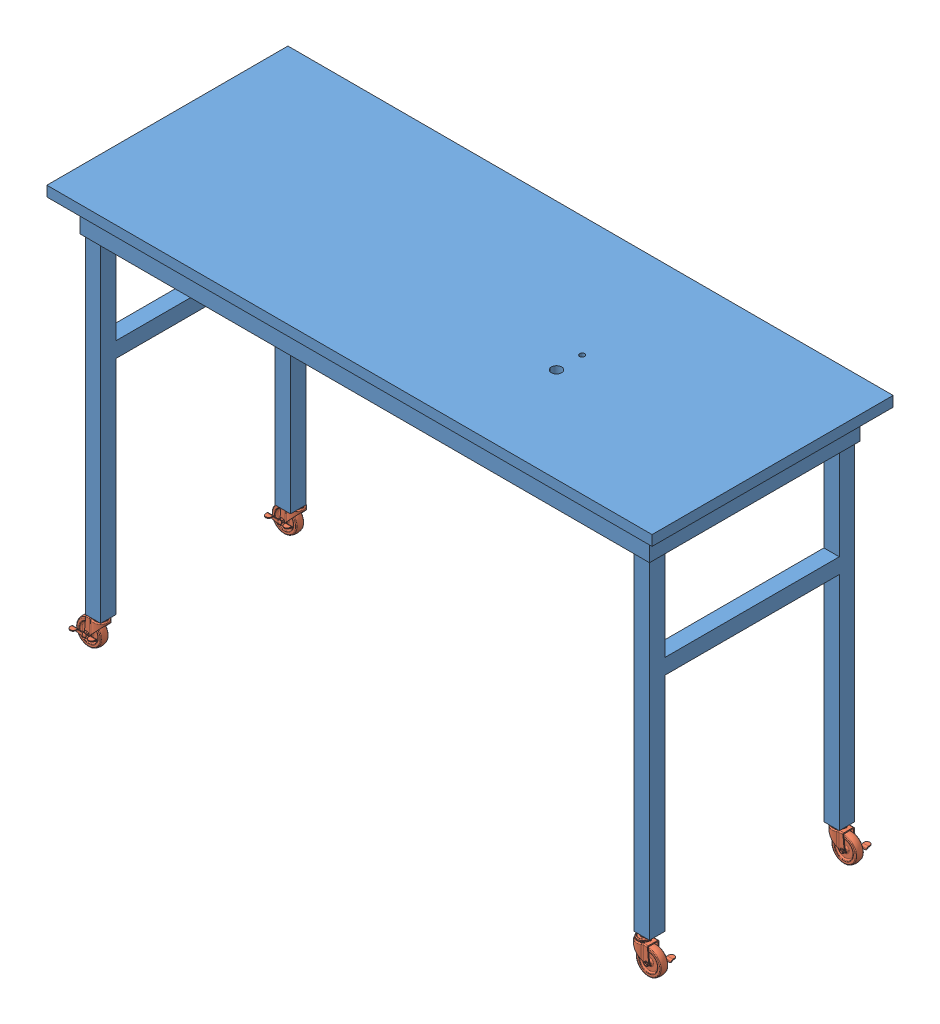
SolidWorks assembly Table, configuration Default. Lengths in mm.
Overall size (1498.6 993.77 596.9).
5 component instances, 2 part files, 2 mates.
Components (placement in the parent):
- Table-1: Table [Default] at origin size (1498.6 917.58 596.9)
- Table Wheel-1: Table Wheel [2834T64] at (-679.45 -879.475 234.95) x (-1 0 0) z (0 0 -1) size (70.25 101.79 50.02)
- Table Wheel-5: Table Wheel [2834T64] at (-679.45 -879.475 -249.2375) x (-1 0 0) z (0 0 -1) size (70.25 101.79 50.02)
- Table Wheel-10: Table Wheel [2834T64] at (679.45 -879.475 -234.95) size (70.25 101.79 50.02)
- Table Wheel-11: Table Wheel [2834T64] at (679.45 -879.475 249.2375) size (70.25 101.79 50.02)
Mates (geometry in assembly coordinates):
- ProfileCenter1: profile center anti-aligned: plane of Table-1 through (0 -892.175 0) normal (0 -1 0); circle of 2834T64_Threaded-Stem Swivel Caster-1
- Parallel1: parallel anti-aligned: plane of Table-1 through (-698.5 -892.175 254) normal (0 0 1); plane of 2834T64_Threaded-Stem Swivel Caster-1 through (-679.45 -879.475 234.95) normal (0 0 -1)
